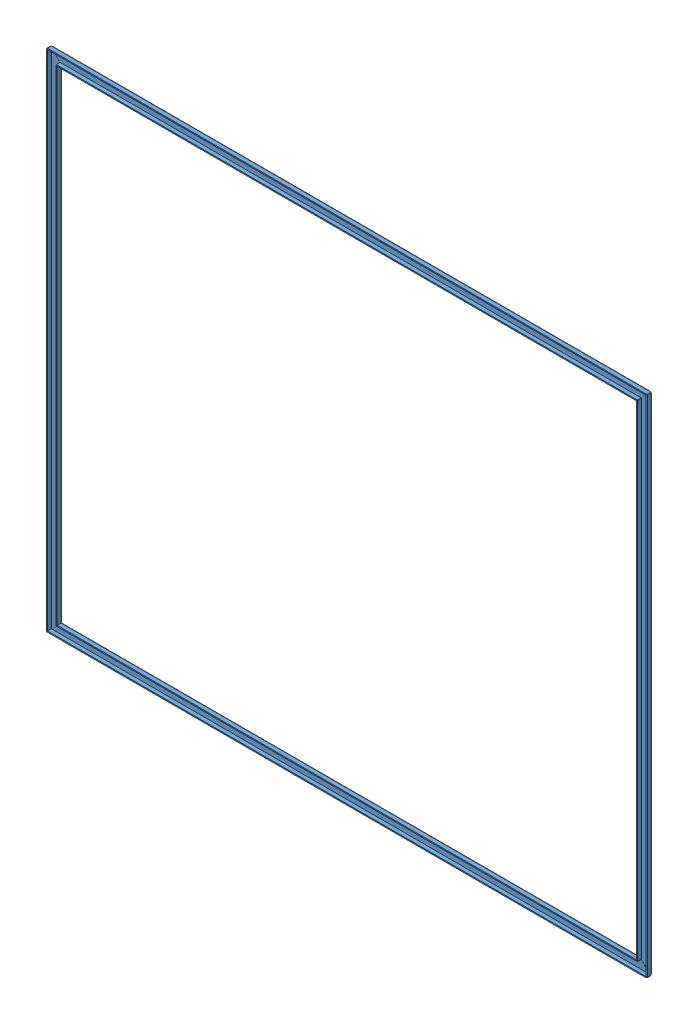
SolidWorks assembly 門蓋補強框, configuration 預設. Lengths in mm.
Overall size (1233.23 1037.93 10.13).
2 component instances, 1 part files, 3 mates.
Components (placement in the parent):
- LB-A54A-02-14-1: LB-A54A-02-14 [預設] at (-1662.9116 513.3252 -5.0633) size (1230.93 1037.93 10.13)
- LB-A54A-02-14-2: LB-A54A-02-14 [預設] at (1638.3282 -467.6819 -5.0633) x (-1 0 0) z (0 0 1) size (1230.93 1037.93 10.13)
Mates (geometry in assembly coordinates):
- 重合/共線/共點1: coincident: plane of LB-A54A-02-14-1 through (-624.745 539.6249 -2.7633) normal (0 0 1); plane of LB-A54A-02-14-2 through (602.1616 -496.3817 -2.7633) normal (0 0 1)
- 重合/共線/共點3: coincident: plane of LB-A54A-02-14-1 through (602.0216 539.4849 -2.9033) normal (1 0 0); plane of LB-A54A-02-14-2 through (602.0216 -496.3817 -3.3033) normal (-1 0 0)
- 重合/共線/共點4: coincident aligned: plane of LB-A54A-02-14-1 through (-624.745 541.7849 -3.3033) normal (0 1 0); plane of LB-A54A-02-14-2 through (602.0216 541.7849 5.0633) normal (0 1 0)
